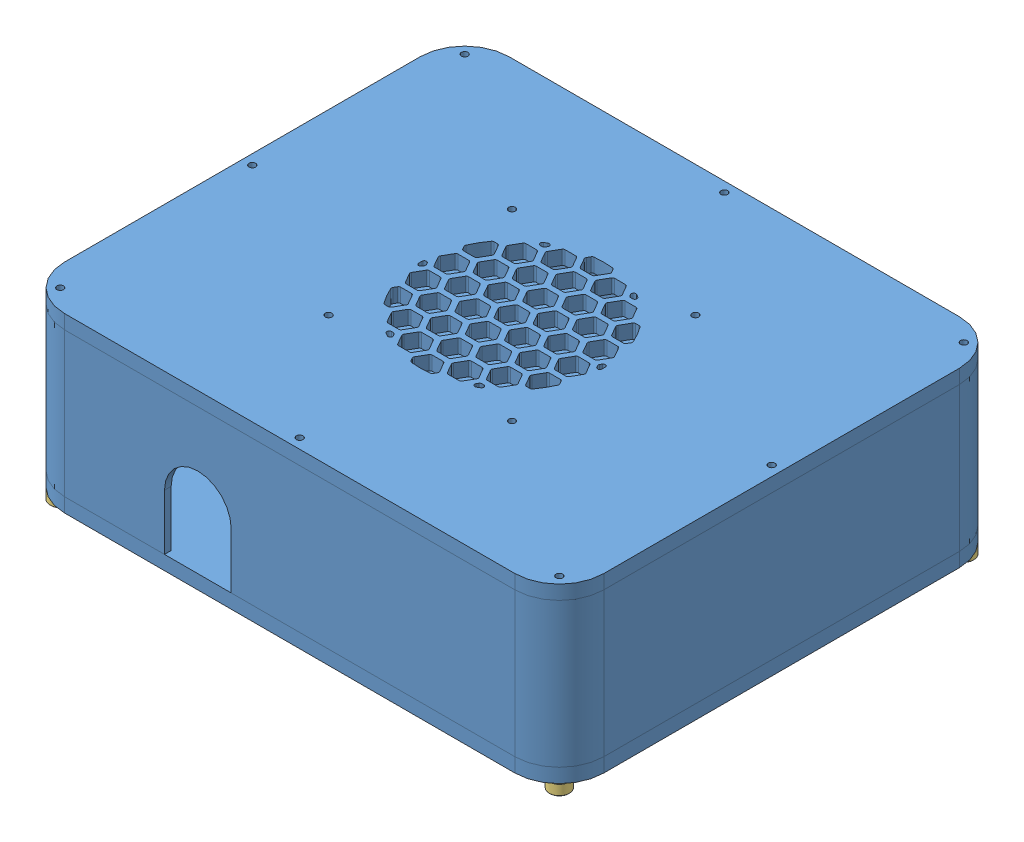
SolidWorks assembly box, configuration Default. Lengths in mm.
Overall size (242.6 82.7 200).
7 component instances, 4 part files, 12 mates.
Components (placement in the parent):
- base-1: base [Default] at (-42.2003 91.1235 297.5217) size (242.6 77.7 200)
- pump mount-1: pump mount [Default] at (158.3997 129.4735 142.5217) size (60 61.48 35)
- feet-10: feet [Default] at (-33.1604 86.1235 106.5616) x (0.203159 0 0.979146) z (-0.979146 0 0.203159) size (9 5 9)
- feet-11: feet [Default] at (-33.1604 86.1235 288.4819) x (0.203159 0 0.979146) z (-0.979146 0 0.203159) size (9 5 9)
- feet-12: feet [Default] at (191.3599 86.1235 106.5616) x (0.203159 0 0.979146) z (-0.979146 0 0.203159) size (9 5 9)
- feet-13: feet [Default] at (191.3599 86.1235 288.4819) x (0.203159 0 0.979146) z (-0.979146 0 0.203159) size (9 5 9)
- box_wire_mount-1: box_wire_mount [Default] at (120.3997 104.9735 100.5217) size (30 15 10)
Mates (geometry in assembly coordinates):
- Concentric1: concentric aligned: circle of base-1; circle of pump mount-1
- Coincident1: coincident anti-aligned: plane of base-1 through (-42.2003 97.4735 297.5217) normal (0 1 0); plane of pump mount-1 through (158.3997 97.4735 177.5217) normal (0 -1 0)
- Concentric21: concentric anti-aligned: cylinder of base-1 through (-33.1604 91.1235 106.5616) axis (0 1 0) radius 1.5; cylinder of feet-10 through (-33.1604 86.1235 106.5616) axis (0 -1 0) radius 1.75
- Coincident921: coincident anti-aligned: plane of base-1 through (-42.2003 91.1235 297.5217) normal (0 -1 0); plane of feet-10 through (-28.7543 91.1235 105.6474) normal (0 1 0)
- Concentric31: concentric anti-aligned: cylinder of base-1 through (-33.1604 91.1235 288.4819) axis (0 1 0) radius 1.5; cylinder of feet-11 through (-33.1604 86.1235 288.4819) axis (0 -1 0) radius 1.75
- Coincident931: coincident anti-aligned: plane of base-1 through (-42.2003 91.1235 297.5217) normal (0 -1 0); plane of feet-11 through (-28.7543 91.1235 287.5677) normal (0 1 0)
- Concentric41: concentric anti-aligned: cylinder of base-1 through (191.3599 91.1235 106.5616) axis (0 1 0) radius 1.5; cylinder of feet-12 through (191.3599 86.1235 106.5616) axis (0 -1 0) radius 1.75
- Coincident941: coincident anti-aligned: plane of base-1 through (-42.2003 91.1235 297.5217) normal (0 -1 0); plane of feet-12 through (195.766 91.1235 105.6474) normal (0 1 0)
- Concentric51: concentric anti-aligned: cylinder of base-1 through (191.3599 91.1235 288.4819) axis (0 1 0) radius 1.5; cylinder of feet-13 through (191.3599 86.1235 288.4819) axis (0 -1 0) radius 1.75
- Coincident951: coincident anti-aligned: plane of base-1 through (-42.2003 91.1235 297.5217) normal (0 -1 0); plane of feet-13 through (195.766 91.1235 287.5677) normal (0 1 0)
- Concentric52: concentric anti-aligned: circle of base-1; circle of box_wire_mount-1
- Coincident952: coincident anti-aligned: plane of base-1 through (-42.2003 97.4735 297.5217) normal (0 1 0); plane of box_wire_mount-1 through (120.3997 97.4735 110.5217) normal (0 -1 0)
